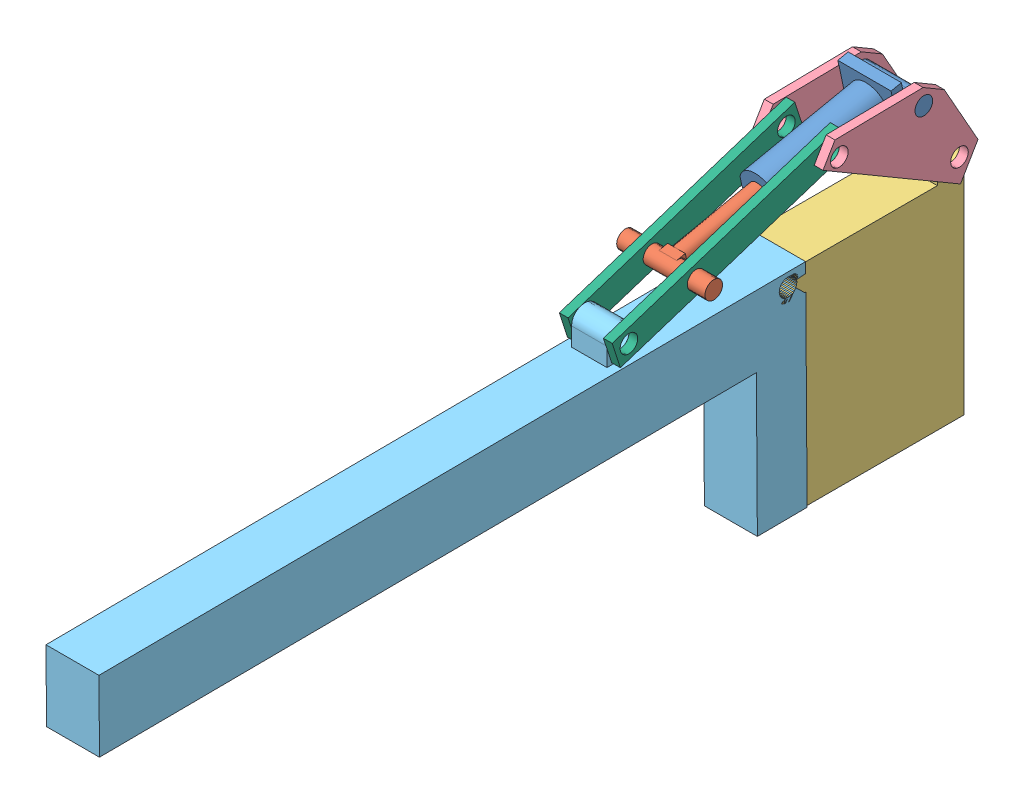
SolidWorks assembly Assembly2, configuration Default. Lengths in mm.
Overall size (254 1028.63 2554.79).
9 component instances, 7 part files, 0 mates.
Components (placement in the parent):
- Assembly2-Part-1-1: Assembly2-Part-1 [Default] at (76.2 1242.8831 -142.0894) x (0 0.979036 0.203686) z (1 0 0) size (130.33 407.02 0)
- Solid1-1: Solid1 [Default] at (76.2 1242.8831 -142.0894) x (0 0.979036 0.203686) z (1 0 0) size (143.39 407.02 203.2)
- Solid1-1-1: Solid1-1 [Default] at (50.8 1127.511 412.4563) x (0 0.979036 0.203686) z (1 0 0) size (50.8 355.6 254)
- Solid1-2-1: Solid1-2 [Default] at (0 -91.3133 48.452) x (0 1 0) z (1 0 0) size (712.68 543.98 152.4)
- Solid1-3-1: Solid1-3 [Default] at (-25.4 897.2587 15.0538) x (0 0.862834 -0.505487) z (1 0 0) size (199.4 458.43 25.4)
- Solid1-3-2: Solid1-3 [Default] at (152.4 897.2587 15.0538) x (0 0.862834 -0.505487) z (1 0 0) size (199.4 458.43 25.4)
- Solid1-4-1: Solid1-4 [Default] at (152.4 753.1066 -111.8329) x (0 -0.999975 -0.007072) z (-1 0 0) size (706.1 2033.19 152.4)
- Solid1-5-1: Solid1-5 [Default] at (152.4 735.1858 865.6407) x (0 -0.951341 -0.308141) z (-1 0 0) size (76.2 685.8 25.4)
- Solid1-5-2: Solid1-5 [Default] at (0 1179.6341 1009.5981) x (0 0.951341 0.308141) z (1 0 0) size (76.2 685.8 25.4)
